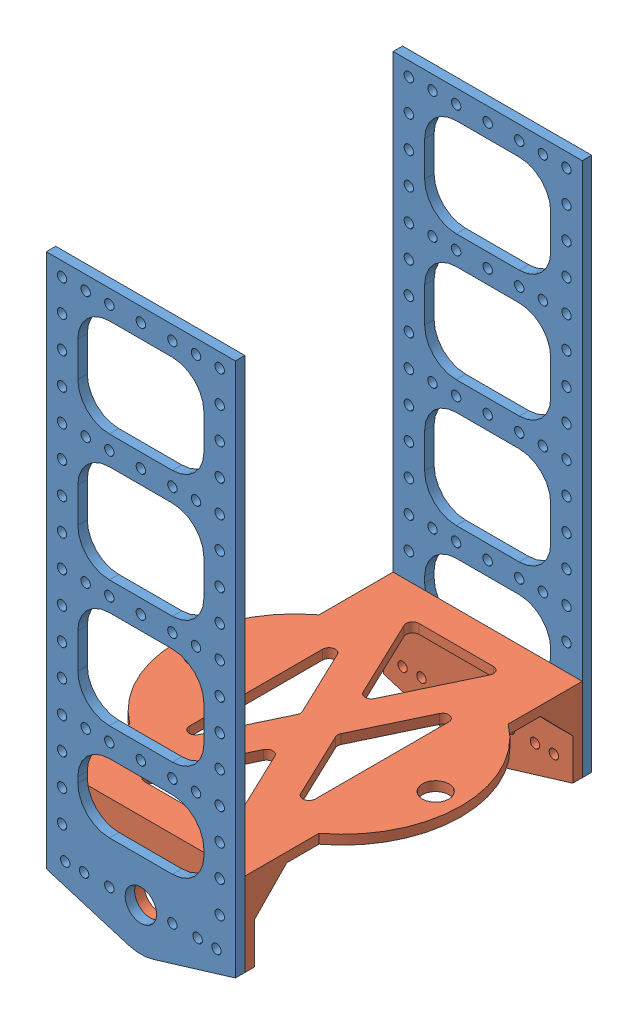
SolidWorks assembly Assem1, configuration Default. Lengths in mm.
Overall size (90.09 178 113).
3 component instances, 2 part files, 4 mates.
Components (placement in the parent):
- vertical_panel-1: vertical_panel [Default] at (-125.8658 -51.56 47.2004) size (60 178 3)
- motor_floor-1: motor_floor [Default] at (-95.4123 -28.2738 157.2004) x (0 0 1) z (1 0 0) size (107 35 90.09)
- vertical_panel-2: vertical_panel [Default] at (-125.8658 -51.56 157.2004) size (60 178 3)
Mates (geometry in assembly coordinates):
- Concentric2: concentric aligned: cylinder of vertical_panel-1 through (-125.4123 -49.7738 50.2004) axis (0 0 -1) radius 5; cylinder of motor_floor-1 through (-125.4123 -49.7738 53.2004) axis (0 0 -1) radius 5
- Concentric3: concentric aligned: cylinder of vertical_panel-1 through (-101.4123 -49.7738 50.2004) axis (0 0 -1) radius 1.5; cylinder of motor_floor-1 through (-101.4123 -49.7738 53.2004) axis (0 0 -1) radius 1.5
- Concentric4: concentric anti-aligned: cylinder of motor_floor-1 through (-125.4123 -49.7738 154.2004) axis (0 0 1) radius 5; cylinder of vertical_panel-2 through (-125.4123 -49.7738 160.2004) axis (0 0 -1) radius 5
- Coincident2: coincident anti-aligned: circle of motor_floor-1; circle of vertical_panel-2
